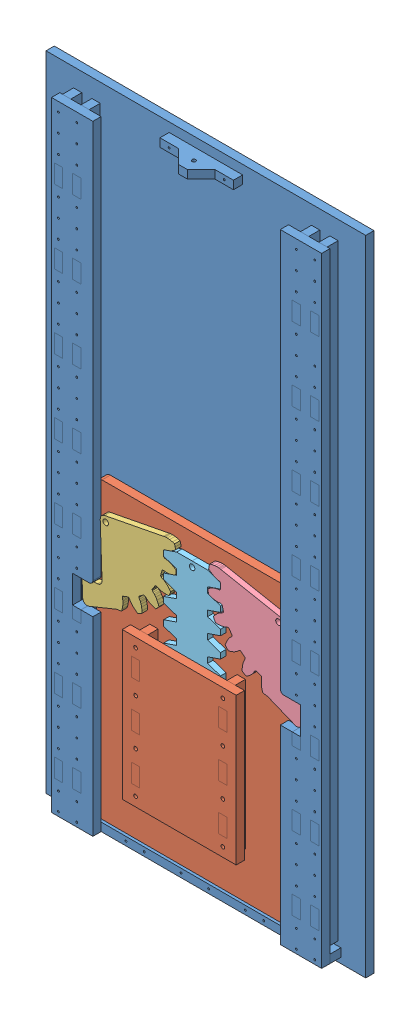
SolidWorks assembly AssemblagePorte, configuration Défaut. Lengths in mm.
Overall size (348 700 38).
5 component instances, 5 part files, 16 mates.
Components (placement in the parent):
- plaque fond-1: plaque fond [Défaut] at origin size (348 700 34)
- volet-1: volet [Défaut] at (0 15 9) size (220 320 29)
- verr_gauche-1: verr_gauche [Défaut] at (9.9026 18.4227 18) x (0.999402 0.034579 0) z (0 0 1) size (154 164.84 6)
- verr_droit-1: verr_droit [Défaut] at (-9.9026 18.4227 18) x (0.999402 -0.034579 0) z (0 0 1) size (104.29 104.26 6)
- verr_centre-1: verr_centre [Défaut] at (0 -4.3572 18) size (80 258 6)
Mates (geometry in assembly coordinates):
- Coïncidente6: coincident: point of plaque fond-1
- Coïncidente1: coincident anti-aligned: plane of plaque fond-1 through (0 0 9) normal (0 0 1); plane of volet-1 through (0 15 9) normal (0 0 -1)
- Coïncidente2: coincident anti-aligned: plane of volet-1 through (0 15 18) normal (0 0 1); plane of verr_gauche-1 through (9.9026 18.4227 18) normal (0 0 -1)
- Coaxiale1: concentric aligned: cylinder of volet-1 through (-94 303 18) axis (0 0 -1) radius 1; cylinder of verr_gauche-1 through (-94 303 24) axis (0 0 -1) radius 3
- Coïncidente3: coincident: plane of volet-1 through (0 15 18) normal (0 0 1); plane of verr_droit-1 through (-9.9026 18.4227 18) normal (0 0 -1)
- Coaxiale2: concentric aligned: cylinder of volet-1 through (94 303 18) axis (0 0 -1) radius 1; cylinder of verr_droit-1 through (94 303 24) axis (0 0 -1) radius 3
- Coïncidente4: coincident anti-aligned: plane of volet-1 through (0 15 18) normal (0 0 1); plane of verr_centre-1 through (0 -4.3572 18) normal (0 0 -1)
- Largeur1: width aligned: plane of plaque fond-1 through (115 0 21) normal (-1 0 0); plane of volet-1 through (-115 0 21) normal (1 0 0); plane of plaque fond-1 through (-110 15 18) normal (-1 0 0); plane of volet-1 through (110 15 18) normal (1 0 0)
- DistanceLimite1: limit distance = 0 mm anti-aligned: plane of volet-1 through (0 15 18) normal (0 -1 0); plane of plaque fond-1 through (0 15 315.1377) normal (0 1 0)
- Largeur2: width anti-aligned: plane of volet-1 through (-43 15 29) normal (1 0 0); plane of verr_centre-1 through (43 15 29) normal (-1 0 0); plane of volet-1 through (-40 163.6428 24) normal (-1 0 0); plane of verr_centre-1 through (40 55.6428 24) normal (1 0 0)
- DistanceLimite2: limit distance = 40.6428 mm aligned: plane of volet-1 through (0 15 18) normal (0 -1 0); plane of verr_centre-1 through (0 55.6428 24) normal (0 -1 0)
- Symétrique1: symmetric aligned: plane of verr_gauche-1 through (-21.1035 17.3499 24) normal (0.999402 0.034579 0); plane of verr_droit-1 through (21.1035 17.3499 24) normal (-0.999402 0.034579 0)
- Coïncidente7: coincident anti-aligned: plane of plaque fond-1 through (0 0 0) normal (0 0 -1)
- Coïncidente8: coincident anti-aligned: plane of plaque fond-1 through (0 0 9) normal (0 -1 0)
- AngleLimite3: limit planar angle = 3.176179 rad anti-aligned: line of verr_gauche-1 through (-31.17 308.2902 24) axis (0.034579 -0.999402 0); line of verr_centre-1 through (-30.9746 308.7344 24) axis (0 -1 0)
- RackPinionMate2: rack pinion = 140 mm: line of verr_centre-1 through (-16.919 297.7439 24) axis (0 -1 0); circle of verr_gauche-1
